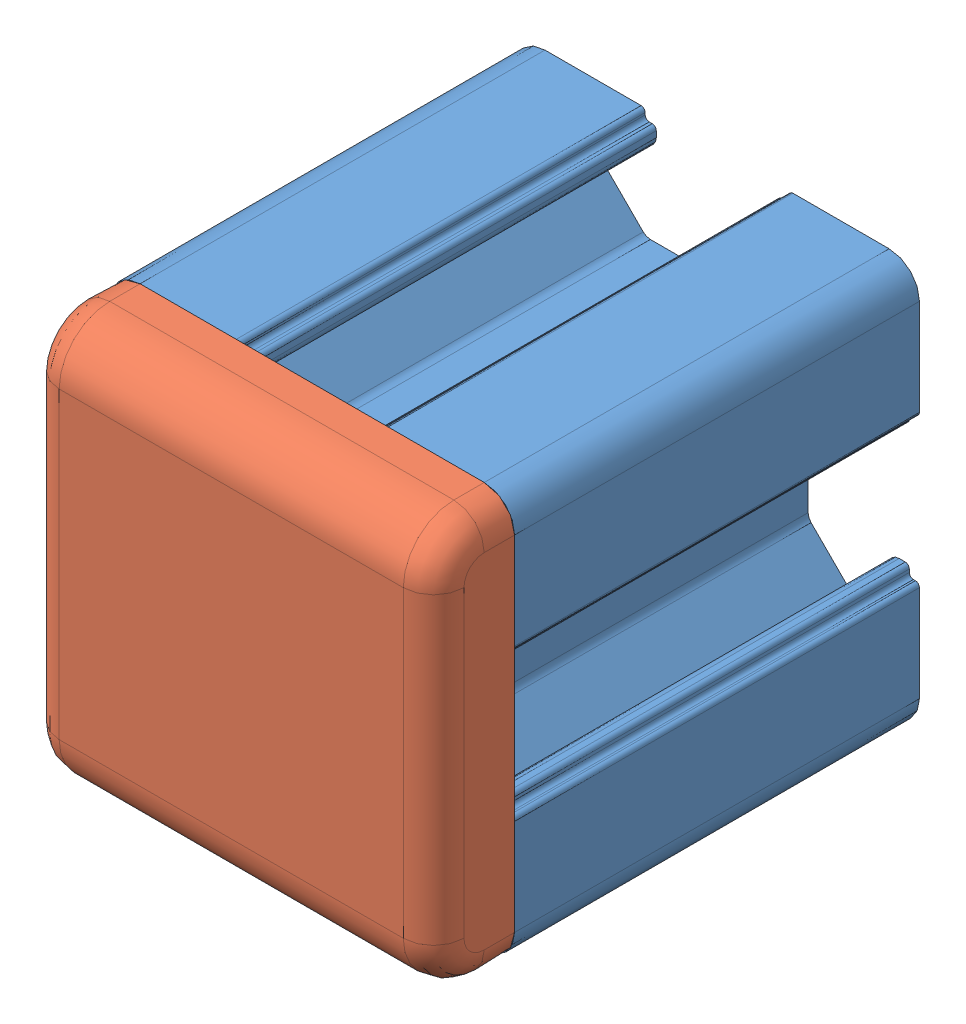
SolidWorks assembly Заглушка20х20СБ, configuration По умолчанию. Lengths in mm.
Overall size (20 20 24).
2 component instances, 2 part files, 6 mates.
Components (placement in the parent):
- 20х20 заглушка-1: 20х20 заглушка [По умолчанию] at origin size (20 20 20)
- Заглушка торцевая 20х20-1: Заглушка торцевая 20х20 [По умолчанию] at (0 0 22) x (0 0 -1) z (1 0 0) size (10 20 20)
Mates (geometry in assembly coordinates):
- Совпадение2: coincident: point of 20х20 заглушка-1
- Параллельность1: parallel anti-aligned: plane of 20х20 заглушка-1 through (0 -10 20) normal (0 -1 0)
- Совпадение4: coincident anti-aligned: plane of 20х20 заглушка-1 through (0 0 0) normal (0 0 -1)
- Совпадение5: coincident anti-aligned: plane of 20х20 заглушка-1 through (0 0 20) normal (0 0 1); plane of Заглушка торцевая 20х20-1 through (-10 -10 20) normal (0 0 -1)
- Совпадение6: coincident aligned: plane of 20х20 заглушка-1 through (0 10 20) normal (0 1 0); plane of Заглушка торцевая 20х20-1 through (-10 10 21.5) normal (0 1 0)
- Совпадение7: coincident aligned: plane of 20х20 заглушка-1 through (10 0 20) normal (1 0 0); plane of Заглушка торцевая 20х20-1 through (10 7.5 21.5) normal (1 0 0)
